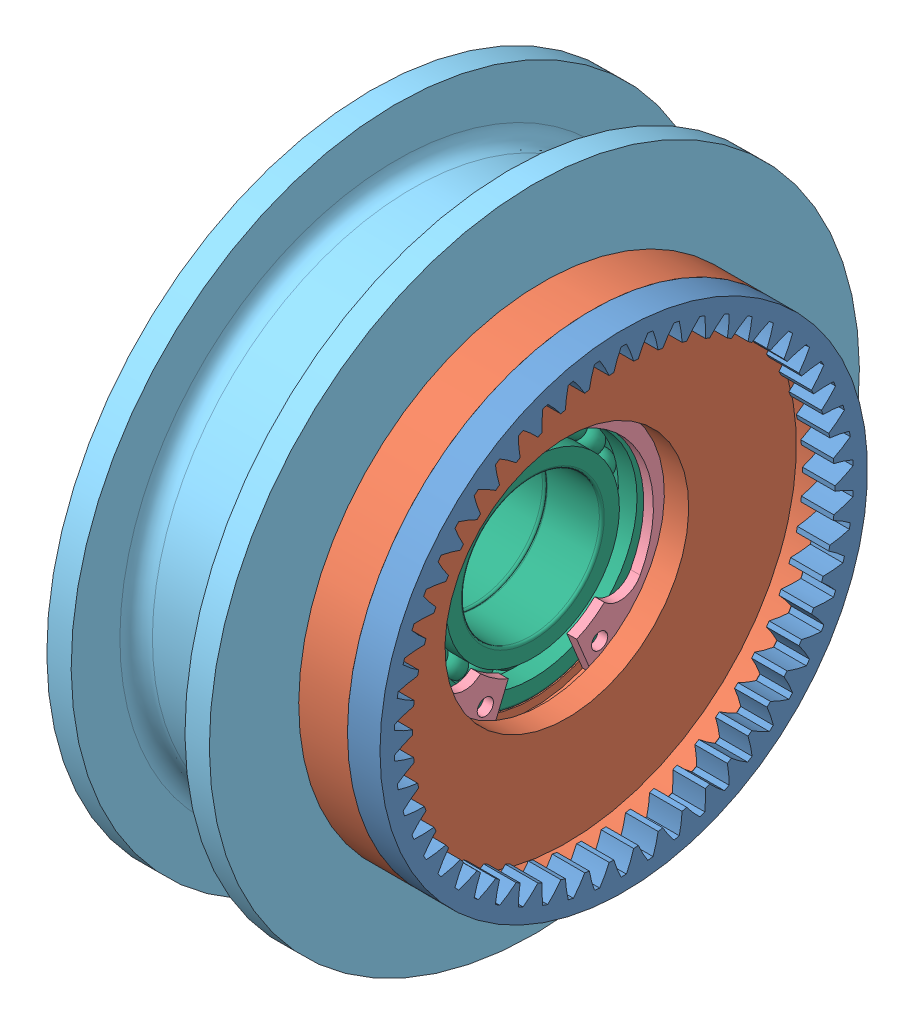
SolidWorks assembly 内齿轮传动, configuration 默认. Lengths in mm.
Overall size (35 92.15 92.15).
11 component instances, 7 part files, 16 mates.
Components (placement in the parent):
- internal spur gear_gb-1: internal spur gear_gb [GB - Internal spur gear 1M 54T 20PA 4FW ---S54S60OD 1.0AF] at (29.8856 -5.5063 0) size (4 60 60)
- 内齿轮输出-1: 内齿轮输出 [默认] at (26.8856 -5.5063 0) x (0 -0.319492 -0.947589) z (1 0 0) size (60 60 31)
- circlips for shaft--type b gb-1: circlips for shaft--type b gb [GB_CONNECTING_PIECE_RINGS_CSB 35] at (4.3856 -4.3766 -0.0239) x (0 0.021133 0.999777) z (-1 0 0) size (39 42.53 1.5)
- circlips for hole--type b gb-4: circlips for hole--type b gb [GB_CONNECTING_PIECE_RINGS_CHB 30] at (23.8856 -5.5063 0) x (0 0 -1) z (1 0 0) size (32.1 30.88 1.2)
- 收卷轮-1: 收卷轮 [默认] at (10.8856 8.1525 31.6232) x (0 -0.399929 -0.916546) z (-1 0 0) size (70 70 24)
  - 收卷轮1-1: 收卷轮1 [默认] at (34.4467 -0.1281 -2) size (70 70 24)
  - deep groove ball bearings gb-4: deep groove ball bearings gb [Rolling bearings 61807 GB 276-94] at (34.4467 -0.1281 -5.5) x (0 0 -1) z (-0.450839 -0.892605 0) size (7 47 47)
  - deep groove ball bearings gb-5: deep groove ball bearings gb [Rolling bearings 61807 GB 276-94] at (34.4467 -0.1281 1.5) x (0 0 -1) z (0.107289 0.994228 0) size (7 47 47)
  - circlips for holes--type a gb-2: circlips for holes--type a gb [GB_CONNECTING_PIECE_RING_RRH 47] at (34.4467 -0.1281 -10.5) x (-0.923728 -0.383049 0) z (0 0 -1) size (50.5 48.58 1.5)
- deep groove ball bearings gb-1: deep groove ball bearings gb [Rolling bearings 61903 GB 276-94] at (19.1856 -5.5063 0) x (1 0 0) z (0 0.43776 0.899092) size (7 30 30)
- deep groove ball bearings gb-2: deep groove ball bearings gb [Rolling bearings 61903 GB 276-94] at (12.1856 -5.5063 0) x (-1 0 0) z (0 -0.924225 -0.381849) size (7 30 30)
Mates (geometry in assembly coordinates):
- 同心21: concentric aligned: cylinder of internal spur gear_gb-1 through (19.8856 -5.5063 0) axis (-1 0 0) radius 30; cylinder of 内齿轮输出-1 through (29.8856 -5.5063 0) axis (-1 0 0) radius 30
- 重合11: coincident anti-aligned: plane of internal spur gear_gb-1 through (29.8856 -5.5063 -26) normal (-1 0 0); plane of 内齿轮输出-1 through (29.8856 -5.5063 0) normal (1 0 0)
- 锁定21: lock: unknown of internal spur gear_gb-1; unknown of 内齿轮输出-1
- 同心51: concentric anti-aligned: cylinder of 内齿轮输出-1 through (29.8856 -5.5063 0) axis (1 0 0) radius 16.1; cylinder of circlips for shaft--type b gb-1 through (5.8856 -5.5063 0) axis (-1 0 0) radius 16.1
- 重合21: coincident anti-aligned: plane of 内齿轮输出-1 through (5.8856 9.7498 -5.1438) normal (-1 0 0); plane of circlips for shaft--type b gb-1 through (5.8856 -4.3766 -0.0239) normal (1 0 0)
- 锁定31: lock: unknown of 内齿轮输出-1; unknown of circlips for shaft--type b gb-1
- 同心6: concentric aligned: cylinder of 内齿轮输出-1 through (29.8856 -5.5063 0) axis (1 0 0) radius 16.0236; cylinder of circlips for hole--type b gb-4 through (22.6856 -5.5063 0) axis (1 0 0) radius 16.05
- 重合3: coincident anti-aligned: plane of 内齿轮输出-1 through (22.6856 9.6775 -5.1194) normal (1 0 0); plane of circlips for hole--type b gb-4 through (22.6856 -5.5063 0) normal (-1 0 0)
- 锁定41: lock: unknown of 内齿轮输出-1; unknown of circlips for hole--type b gb-4
- 锁定51: lock: unknown of internal spur gear_gb-1; unknown of 内齿轮输出-1
- 同心71: concentric anti-aligned: cylinder of 内齿轮输出-1 through (3.8856 -5.5063 0) axis (1 0 0) radius 17.5; cylinder of 收卷轮-1/deep groove ball bearings gb-4 through (9.4142 -5.5063 0) axis (-1 0 0) radius 17.5
- 重合41: coincident anti-aligned: plane of circlips for shaft--type b gb-1 through (5.8856 -4.3766 -0.0239) normal (1 0 0); plane of 收卷轮-1/deep groove ball bearings gb-5 through (5.8856 0.3297 18.6062) normal (-1 0 0)
- 重合51: coincident anti-aligned: plane of deep groove ball bearings gb-1 through (15.6856 7.98 -6.5664) normal (-1 0 0); plane of deep groove ball bearings gb-2 through (15.6856 0.2214 -13.8634) normal (1 0 0)
- 同心81: concentric anti-aligned: cylinder of deep groove ball bearings gb-1 through (12.2142 -5.5063 0) axis (-1 0 0) radius 8.5; cylinder of deep groove ball bearings gb-2 through (19.157 -5.5063 0) axis (1 0 0) radius 8.5
- 同心91: concentric anti-aligned: cylinder of 内齿轮输出-1 through (23.8856 -5.5063 0) axis (1 0 0) radius 15; cylinder of deep groove ball bearings gb-1 through (12.2142 -5.5063 0) axis (-1 0 0) radius 8.5
- 重合61: coincident anti-aligned: plane of 内齿轮输出-1 through (8.6856 -5.5063 0) normal (1 0 0); plane of deep groove ball bearings gb-2 through (8.6856 0.2214 -13.8634) normal (-1 0 0)
